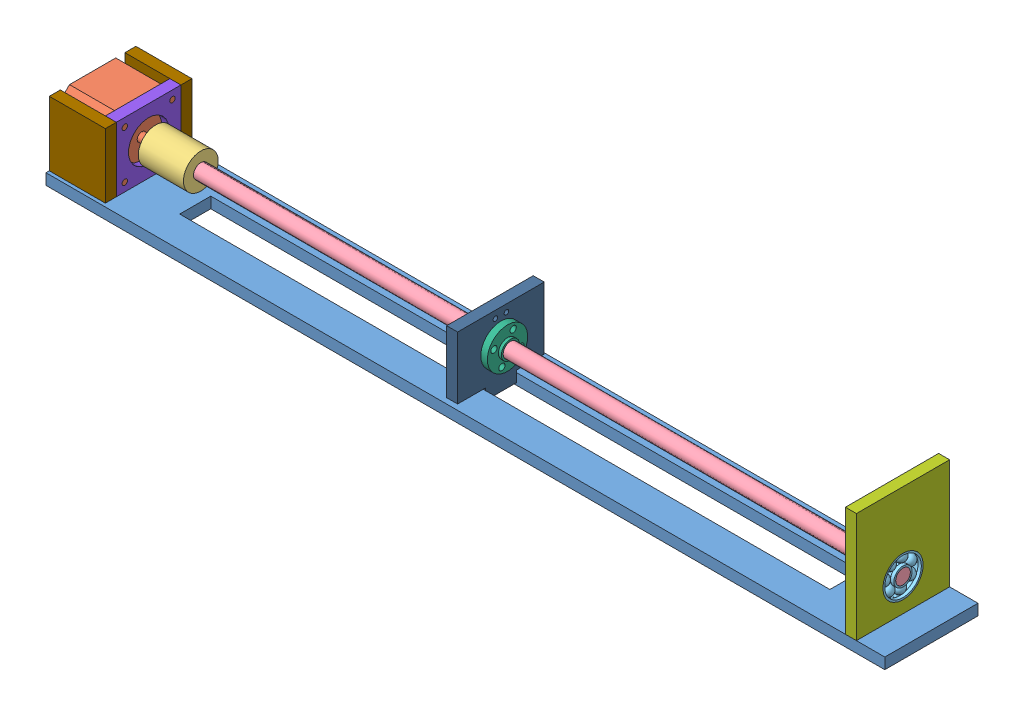
SolidWorks assembly finalasy, configuration Default. Lengths in mm.
Overall size (457.2 66 50.8).
11 component instances, 10 part files, 24 mates.
Components (placement in the parent):
- Base-1: Base [Default] at (10.9518 219.7985 350.7169) size (457.2 6 50.8)
- NEMA14-1: NEMA14 [Default] at (10.9518 225.7985 342.9169) size (40.79 35.2 35.2)
- coupling-1: coupling [Default] at (69.9418 243.3985 325.3169) x (0 1 0) z (0 0 1) size (19 24.6 19)
- rod-1: rod [Default] at (452.6918 243.3985 325.3169) x (0 0 1) z (-1 0 0) size (8 8 400)
- bearing-1: bearing [Default] at (448.1489 243.3985 325.3169) x (0 -0.381849 0.924225) z (0 0.924225 0.381849) size (22 7 22)
- nut-1: nut [Default] at (233.517 243.3985 325.3169) x (0 0.38201 0.924158) z (1 0 0) size (22 22 16.09)
- end wal-1: end wal [Default] at (452.6918 0 650.6339) x (0 0 1) z (-1 0 0) size (50.8 66 6)
- stepper mount-1: stepper mount [Default] at (41.4918 0 0) x (0 0 1) z (-1 0 0) size (35.2 41.2 6)
- stepper mount side-1: stepper mount side [Default] at (52.4437 0 301.7169) size (30.54 41.2 6)
- stepper mount side-2: stepper mount side [Default] at (52.4437 0 342.9169) size (30.54 41.2 6)
- lasser mt-1: lasser mt [Default] at (227.517 0 650.6339) x (0 0 -1) z (1 0 0) size (47.2 39.95 6)
Mates (geometry in assembly coordinates):
- Concentric1: concentric aligned: cylinder of NEMA14-1 through (51.7418 243.3985 325.3169) axis (-1 0 0) radius 2.5; cylinder of coupling-1 through (69.9428 243.3985 325.3169) axis (-1 0 0) radius 2.5
- Distance1: distance = 7.6 mm anti-aligned: plane of NEMA14-1 through (37.7418 243.3985 325.3169) normal (1 0 0); plane of coupling-1 through (45.3418 243.3985 325.3169) normal (-1 0 0)
- Coincident2: coincident anti-aligned: plane of coupling-1 through (52.6918 243.3985 325.3169) normal (1 0 0); plane of rod-1 through (52.6918 243.3985 325.3169) normal (-1 0 0)
- Coincident3: coincident anti-aligned: cylinder of coupling-1 through (52.6918 243.3985 325.3169) axis (1 0 0) radius 4; circle of rod-1
- Coincident4: coincident aligned: plane of rod-1 through (452.6918 243.3985 325.3169) normal (1 0 0); plane of bearing-1 through (452.6918 244.9259 321.62) normal (1 0 0)
- Concentric2: concentric aligned: cylinder of coupling-1 through (45.3418 243.3985 325.3169) axis (1 0 0) radius 9.5; cylinder of bearing-1 through (498.1489 243.3985 325.3169) axis (1 0 0) radius 4
- Coincident7: coincident anti-aligned: plane of Base-1 through (10.9518 225.7985 350.7169) normal (0 1 0); plane of NEMA14-1 through (10.9518 225.7985 342.9169) normal (0 -1 0)
- Coincident8: coincident: moEndPointRef_w of Base-1; moEndPointRef_w of NEMA14-1
- Parallel3: parallel aligned: plane of coupling-1 through (69.9418 243.3985 325.3169) normal (1 0 0); plane of nut-1 through (237.117 243.3985 325.3169) normal (1 0 0)
- Concentric3: concentric anti-aligned: cylinder of coupling-1 through (45.3418 243.3985 325.3169) axis (1 0 0) radius 9.5; cylinder of nut-1 through (237.117 243.3985 325.3169) axis (-1 0 0) radius 11
- Coincident10: coincident anti-aligned: plane of Base-1 through (446.6918 219.7975 316.8503) normal (1 0 0); plane of end wal-1 through (446.6918 0 650.6339) normal (-1 0 0)
- Coincident11: coincident anti-aligned: plane of Base-1 through (452.6918 219.7975 333.7836) normal (0 0 -1); plane of end wal-1 through (446.6918 219.7985 333.7836) normal (0 0 1)
- Coincident12: coincident aligned: plane of Base-1 through (10.9518 219.7985 350.7169) normal (0 -1 0); plane of end wal-1 through (446.6918 219.7985 316.8503) normal (0 -1 0)
- Coincident13: coincident anti-aligned: plane of Base-1 through (35.4918 219.7975 319.4503) normal (1 0 0); plane of stepper mount-1 through (35.4918 0 0) normal (-1 0 0)
- Coincident14: coincident anti-aligned: plane of Base-1 through (35.4918 219.7975 331.1836) normal (0 0 -1); plane of stepper mount-1 through (35.4918 219.7985 331.1836) normal (0 0 1)
- Coincident15: coincident aligned: plane of Base-1 through (10.9518 219.7985 350.7169) normal (0 -1 0); plane of stepper mount-1 through (35.4918 219.7985 319.4503) normal (0 -1 0)
- Coincident16: coincident anti-aligned: plane of Base-1 through (21.1318 219.7975 307.7169) normal (0 0 -1); plane of stepper mount side-1 through (52.4437 0 307.7169) normal (0 0 1)
- Coincident17: coincident anti-aligned: plane of Base-1 through (21.1318 219.7975 301.7169) normal (1 0 0); plane of stepper mount side-1 through (21.1318 219.7985 307.7169) normal (-1 0 0)
- Coincident18: coincident aligned: plane of Base-1 through (10.9518 219.7985 350.7169) normal (0 -1 0); plane of stepper mount side-1 through (31.3118 219.7985 307.7169) normal (0 -1 0)
- Coincident20: coincident anti-aligned: plane of Base-1 through (21.1318 219.7975 348.9169) normal (0 0 -1); plane of stepper mount side-2 through (52.4437 0 348.9169) normal (0 0 1)
- Coincident21: coincident anti-aligned: plane of Base-1 through (31.3118 219.7975 342.9169) normal (-1 0 0); plane of stepper mount side-2 through (31.3118 225.7985 348.9169) normal (1 0 0)
- Coincident22: coincident aligned: plane of Base-1 through (10.9518 219.7985 350.7169) normal (0 -1 0); plane of stepper mount side-2 through (31.3118 219.7985 348.9169) normal (0 -1 0)
- Coincident23: coincident anti-aligned: plane of nut-1 through (233.517 243.3985 325.3169) normal (-1 0 0); plane of lasser mt-1 through (233.517 0 650.6339) normal (1 0 0)
- Concentric4: concentric anti-aligned: cylinder of nut-1 through (223.517 243.3985 325.3169) axis (1 0 0) radius 5; cylinder of lasser mt-1 through (233.517 243.3985 325.3169) axis (-1 0 0) radius 5
